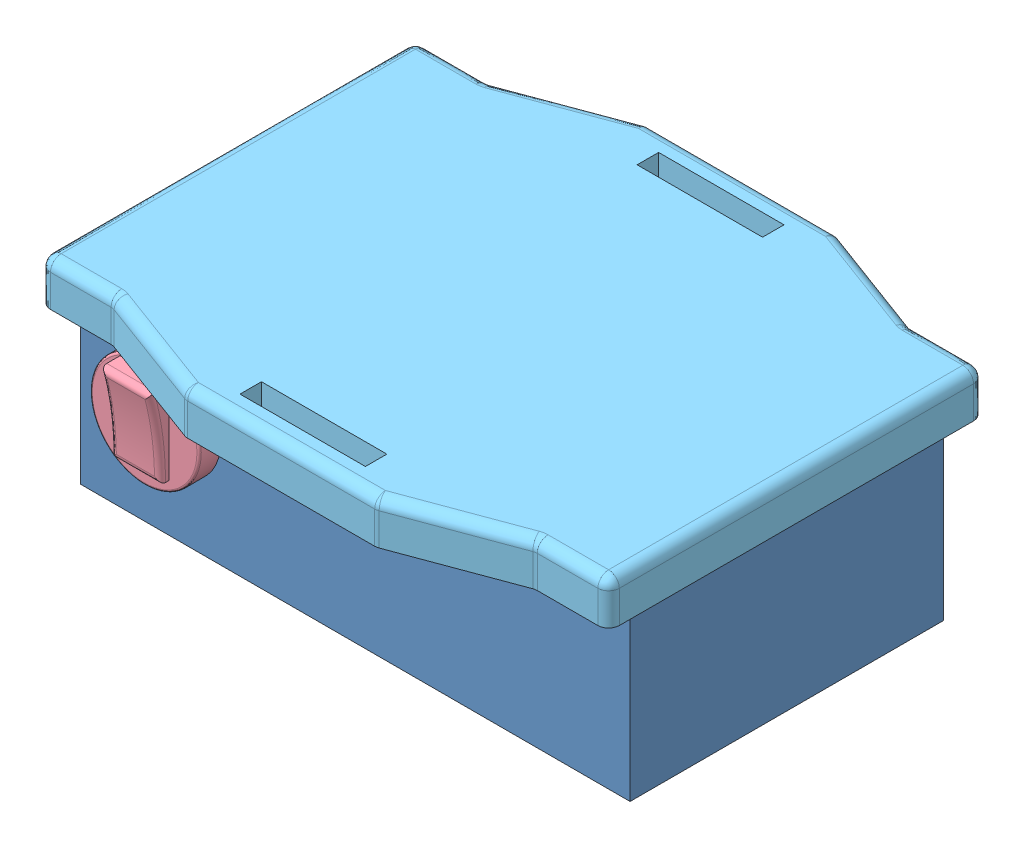
SolidWorks assembly DrumLineAssembly, configuration Default. Lengths in mm.
Overall size (132.5 49 107.5).
5 component instances, 5 part files, 16 mates.
Components (placement in the parent):
- ElectronicsHousingV2-1: ElectronicsHousingV2 [Default] at origin size (128 45 73)
- 12vBatteryPack-1: 12vBatteryPack [Default] at (25.25 0 0) x (0 0 -1) z (1 0 0) size (59 33.5 63.5)
- PercussionBoard-1: PercussionBoard [Default] at (-16.25 19.15 0) x (0 -1 0) z (0 0 -1) size (38.3 12 49.96)
- OnOffSwitch-1: OnOffSwitch [Default] at (-44 21 8.5) size (25.4 25.4 37.79)
- TopCover-1: TopCover [Default] at (0 41 0) x (0 0 1) z (-1 0 0) size (107.5 10 132.5)
Mates (geometry in assembly coordinates):
- Coincident1: coincident aligned: plane of ElectronicsHousingV2-1 through (0 0 0) normal (0 0 1); plane of assembly through (0 0 0) normal (0 0 1)
- Coincident2: coincident aligned: plane of ElectronicsHousingV2-1 through (0 0 0) normal (0 1 0); plane of assembly through (0 0 0) normal (0 1 0)
- Coincident3: coincident aligned: plane of ElectronicsHousingV2-1 through (0 0 0) normal (1 0 0); plane of assembly through (0 0 0) normal (1 0 0)
- Parallel1: parallel anti-aligned: plane of ElectronicsHousingV2-1 through (60 41 0) normal (-1 0 0); plane of 12vBatteryPack-1 through (57 33.5 -29.5) normal (1 0 0)
- Width1: width aligned: plane of ElectronicsHousingV2-1 through (0 41 -32.5) normal (0 0 1); plane of ElectronicsHousingV2-1 through (0 41 32.5) normal (0 0 -1); plane of 12vBatteryPack-1 through (-6.5 33.5 29.5) normal (0 0 1); plane of 12vBatteryPack-1 through (-6.5 33.5 -29.5) normal (0 0 -1)
- Distance2: distance = 3 mm anti-aligned: plane of 12vBatteryPack-1 through (57 33.5 -29.5) normal (1 0 0); plane of ElectronicsHousingV2-1 through (60 41 0) normal (-1 0 0)
- Parallel2: parallel aligned: plane of ElectronicsHousingV2-1 through (0 0 0) normal (0 1 0); plane of PercussionBoard-1 through (-17.75 38.3 24.98) normal (0 1 0)
- Coincident6: coincident anti-aligned: plane of ElectronicsHousingV2-1 through (0 0 0) normal (0 1 0); plane of 12vBatteryPack-1 through (25.25 0 0) normal (0 -1 0)
- Parallel3: parallel anti-aligned: plane of ElectronicsHousingV2-1 through (60 41 0) normal (-1 0 0); plane of PercussionBoard-1 through (-16.25 19.15 0) normal (1 0 0)
- Width2: width anti-aligned: plane of ElectronicsHousingV2-1 through (0 41 32.5) normal (0 0 -1); plane of ElectronicsHousingV2-1 through (0 41 -32.5) normal (0 0 1); plane of PercussionBoard-1 through (-17.75 0 24.98) normal (0 0 1); plane of PercussionBoard-1 through (-17.75 0 -24.98) normal (0 0 -1)
- Coincident8: coincident anti-aligned: plane of ElectronicsHousingV2-1 through (0 0 0) normal (0 1 0); plane of PercussionBoard-1 through (-17.75 0 24.98) normal (0 -1 0)
- Width3: width anti-aligned: plane of ElectronicsHousingV2-1 through (-19.5 32 -21.3) normal (1 0 0); plane of ElectronicsHousingV2-1 through (-14.5 32 -32.5) normal (-1 0 0); plane of PercussionBoard-1 through (-17.75 19.15 0) normal (-1 0 0); plane of PercussionBoard-1 through (-16.25 19.15 0) normal (1 0 0)
- Concentric1: concentric aligned: circle of ElectronicsHousingV2-1; circle of OnOffSwitch-1
- Parallel4: parallel aligned: plane of ElectronicsHousingV2-1 through (-64 41 -36.5) normal (-1 0 0); plane of OnOffSwitch-1 through (-49.715 21.9775 44.3553) normal (-1 0 0)
- Coincident10: coincident anti-aligned: plane of ElectronicsHousingV2-1 through (64 41 36.5) normal (0 0 1); plane of OnOffSwitch-1 through (-44 21 36.5) normal (0 0 -1)
- ProfileCenter1: profile center anti-aligned: plane of TopCover-1 through (0 41 0) normal (0 -1 0); plane of ElectronicsHousingV2-1 through (0 41 0) normal (0 1 0)
